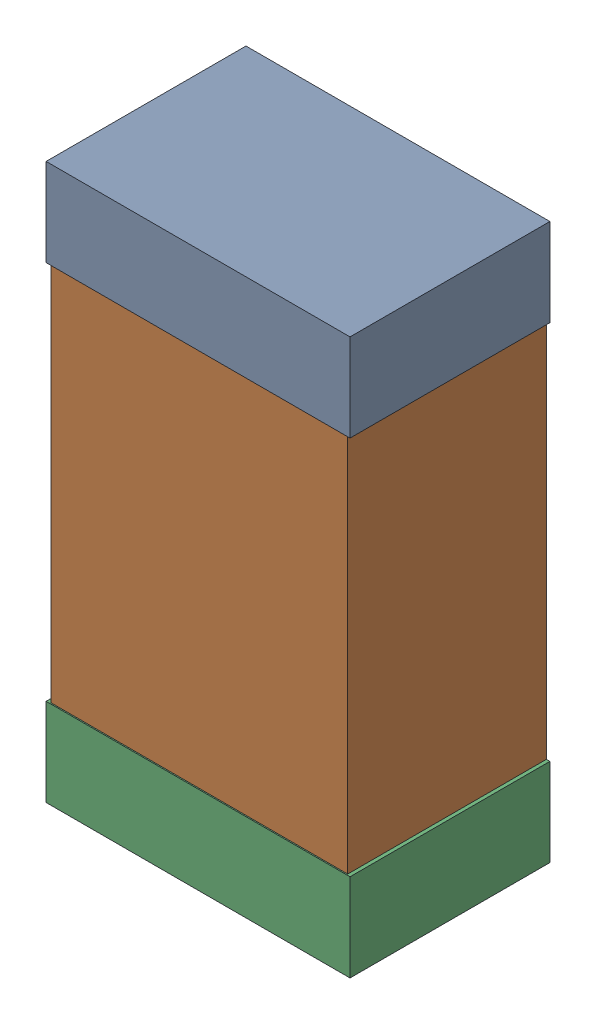
SolidWorks assembly C1Kanaloa_v2.0.0_GPIO_b, configuration Default. Lengths in mm.
Overall size (1.3 2.38 0.85).
6 component instances, 2 part files, 0 mates.
Components (placement in the parent):
- 330415056-1: 330415056 [Default] at (77.089 77.327 0) size (1.3 0.38 0.85)
  - Extruded_2-1: Extruded_2 [Default] at origin size (1.3 0.38 0.85)
- 352877008-1: 352877008 [Default] at (77.089 76.327 0) size (1.27 2.2 0.85)
  - Extruded_3-1: Extruded_3 [Default] at origin size (1.27 2.2 0.85)
- 330415056-2: 330415056 [Default] at (77.089 75.327 0) size (1.3 0.38 0.85)
  - Extruded_2-1: Extruded_2 [Default] at origin size (1.3 0.38 0.85)
